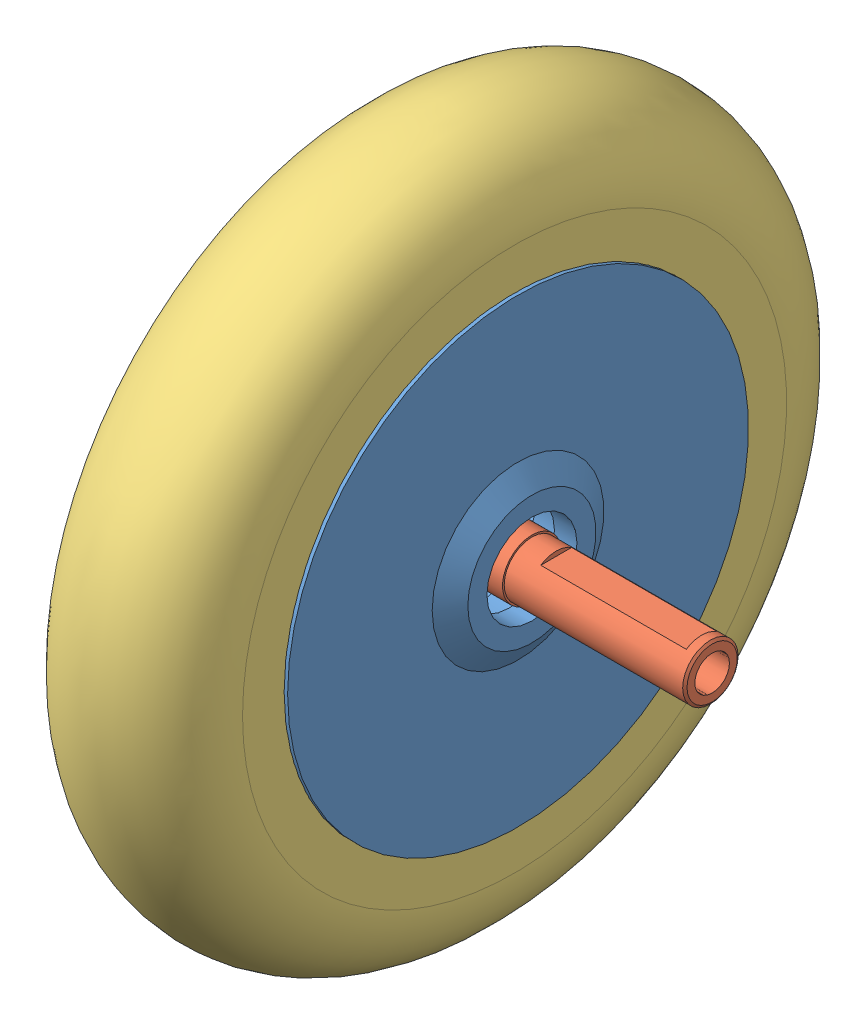
SolidWorks assembly MotorWheel, configuration Default. Lengths in mm.
Overall size (117 195.6 195.6).
3 component instances, 3 part files, 4 mates.
Components (placement in the parent):
- WheelMotor-1: WheelMotor [Default] at (0 -0.4862 -4.3272) size (65 133 133)
- WheelMotorShaft-1: WheelMotorShaft [Default] at (29 -0.4862 -4.3272) size (80 17 17)
- WheelMotorTire-1: WheelMotorTire [Default] at (0.5 -0.4862 -4.3272) size (47 195.6 195.6)
Mates (geometry in assembly coordinates):
- Concentric1: concentric anti-aligned: cylinder of WheelMotor-1 through (-84.606 -0.4862 -4.3272) axis (-1 0 0) radius 13; cylinder of WheelMotorShaft-1 through (81 -0.4862 -4.3272) axis (1 0 0) radius 8.5
- Concentric2: concentric aligned: cylinder of WheelMotor-1 through (-84.606 -0.4862 -4.3272) axis (-1 0 0) radius 59.5; cylinder of WheelMotorTire-1 through (-95.4057 -0.4862 -4.3272) axis (-1 0 0) radius 60.8
- Coincident1: coincident anti-aligned: plane of WheelMotor-1 through (-18 66.0138 -4.3272) normal (1 0 0); plane of WheelMotorTire-1 through (-18 -0.4862 -4.3272) normal (-1 0 0)
- Distance2: distance = 52 mm aligned: plane of WheelMotor-1 through (29 -0.4862 -4.3272) normal (1 0 0); plane of WheelMotorShaft-1 through (81 -0.4862 -4.3272) normal (1 0 0)
